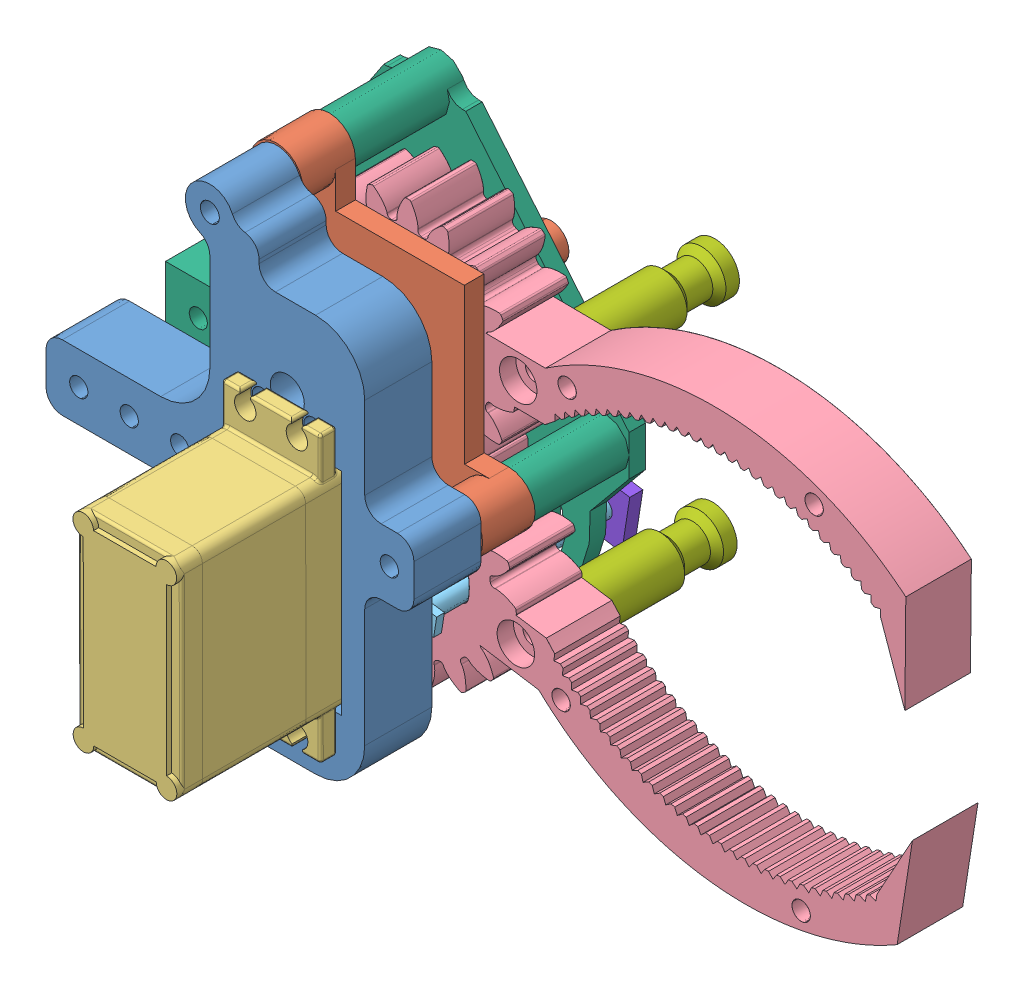
SolidWorks assembly GripperSlotAssemblyNoTop, configuration Default. Lengths in mm.
Overall size (145.62 102 92.76).
10 component instances, 8 part files, 25 mates.
Components (placement in the parent):
- ServoHolderBracketNew-1: ServoHolderBracketNew [Default] at (6.3729 56.0848 81.9147) size (71.28 93.53 13)
- MiddlePlate-1: MiddlePlate [Default] at (38.1308 58.971 75.5647) x (-0.001548 0.999999 0) z (-0.999999 -0.001548 0) size (94.08 38.1 44.92)
- Servo 20kg elbow and gripper2-1: Servo 20kg elbow and gripper2 [Default] at (53.154 53.241 126.4147) x (0.001242 -0.999999 0) z (0.999999 0.001242 0) size (55.1 45.65 20.12)
- NewFingerSlot-1: NewFingerSlot [Default] at (53.0922 81.5431 59.0547) x (0.009287 0.999957 0) z (0 0 1) size (42.33 117.57 12.7)
- NewFingerSlot-2: NewFingerSlot [Default] at (53.1512 43.4431 71.7547) x (-0.154386 -0.988011 0) z (0 0 -1) size (42.33 117.57 12.7)
- ServoHornWithSlotAttachment-1: ServoHornWithSlotAttachment [Default] at (53.1512 43.4431 79.6147) x (-0.988011 0.154386 0) z (0 0 1) size (23.98 21 43)
- GripperTopBracketNew-1: GripperTopBracketNew [Default] at (77.7117 20.5271 50.0377) x (-0.001548 0.999999 0) z (0 0 1) size (93.53 71.27 21.72)
- RubberBandStandOff-1: RubberBandStandOff [Default] at (74.6962 82.9427 46.3547) x (0.53743 -0.843308 0) z (0.843308 0.53743 0) size (9.53 25.4 9.53)
- RubberBandStandOff-2: RubberBandStandOff [Default] at (74.2353 38.5289 46.3547) x (0.873096 -0.487548 0) z (0.487548 0.873096 0) size (9.53 25.4 9.53)
- Connector Bracket-1: Connector Bracket [Default] at (58.9546 47.6779 43.8147) x (0.988011 -0.154386 0) z (0.154386 0.988011 0) size (19.05 2.54 10.16)
Mates (geometry in assembly coordinates):
- Concentric1: concentric aligned: circle of ServoHolderBracketNew-1; circle of MiddlePlate-1
- Coincident3: coincident anti-aligned: plane of ServoHolderBracketNew-1 through (6.3729 56.0848 81.9147) normal (0 0 -1); plane of MiddlePlate-1 through (38.0603 104.4687 81.9147) normal (0 0 1)
- Lock1: lock: unknown of ServoHolderBracketNew-1; unknown of MiddlePlate-1
- Concentric7: concentric aligned: circle of ServoHolderBracketNew-1; circle of Servo 20kg elbow and gripper2-1
- Coincident7: coincident anti-aligned: plane of ServoHolderBracketNew-1 through (6.3729 56.0848 94.9147) normal (0 0 1); plane of Servo 20kg elbow and gripper2-1 through (58.1851 28.1972 94.9147) normal (0 0 -1)
- Lock2: lock: unknown of ServoHolderBracketNew-1; unknown of Servo 20kg elbow and gripper2-1
- Concentric10: concentric anti-aligned: circle of MiddlePlate-1; circle of NewFingerSlot-1
- Coincident9: coincident anti-aligned: plane of MiddlePlate-1 through (38.1308 58.971 71.7547) normal (0 0 -1); plane of NewFingerSlot-1 through (53.0922 81.5431 71.7547) normal (0 0 1)
- Concentric11: concentric aligned: circle of MiddlePlate-1; circle of NewFingerSlot-2
- Coincident10: coincident anti-aligned: plane of MiddlePlate-1 through (38.1308 58.971 71.7547) normal (0 0 -1); plane of NewFingerSlot-2 through (53.1512 43.4431 71.7547) normal (0 0 1)
- GearMate4: gear = 7.112 : 7.112 mm: circle of NewFingerSlot-2; circle of NewFingerSlot-1
- Concentric13: concentric anti-aligned: circle of ServoHornWithSlotAttachment-1; circle of MiddlePlate-1
- Coincident11: coincident anti-aligned: plane of ServoHolderBracketNew-1 through (6.3729 56.0848 81.9147) normal (0 0 -1); plane of ServoHornWithSlotAttachment-1 through (53.1512 43.4431 81.9147) normal (0 0 1)
- Slot1: slot anti-aligned: cylinder of ServoHornWithSlotAttachment-1 through (63.1894 41.8745 42.1147) axis (0 0 1) radius 1.778; cylinder of NewFingerSlot-2 through (53.1512 43.4431 71.7547) axis (0 0 -1) radius 12.065; cylinder of NewFingerSlot-2 through (43.113 45.0117 71.7547) axis (0 0 -1) radius 1.905
- Concentric14: concentric aligned: circle of MiddlePlate-1; circle of GripperTopBracketNew-1
- Concentric15: concentric aligned: circle of MiddlePlate-1; circle of GripperTopBracketNew-1
- Coincident14: coincident anti-aligned: plane of MiddlePlate-1 through (38.1308 58.971 71.7547) normal (0 0 -1); plane of GripperTopBracketNew-1 through (38.0567 104.4738 71.7547) normal (0 0 1)
- Slot2: slot anti-aligned: cylinder of ServoHornWithSlotAttachment-1 through (63.1894 41.8745 42.1147) axis (0 0 1) radius 1.778; cylinder of GripperTopBracketNew-1 through (53.1512 43.4431 53.2127) axis (0 0 -1) radius 12.065; cylinder of GripperTopBracketNew-1 through (43.0814 42.0924 55.1177) axis (0 0 -1) radius 1.905
- Concentric17: concentric anti-aligned: circle of NewFingerSlot-1; circle of RubberBandStandOff-1
- Coincident17: coincident anti-aligned: plane of NewFingerSlot-1 through (53.0922 81.5431 59.0547) normal (0 0 -1); plane of RubberBandStandOff-1 through (77.2557 78.9264 59.0547) normal (0 0 1)
- Concentric18: concentric anti-aligned: circle of NewFingerSlot-2; circle of RubberBandStandOff-2
- Coincident19: coincident anti-aligned: plane of NewFingerSlot-2 through (53.1512 43.4431 59.0547) normal (0 0 -1); plane of RubberBandStandOff-2 through (78.3935 36.207 59.0547) normal (0 0 1)
- Concentric19: concentric aligned: circle of MiddlePlate-1; circle of Connector Bracket-1
- Concentric20: concentric aligned: circle of ServoHornWithSlotAttachment-1; circle of Connector Bracket-1
- Coincident22: coincident anti-aligned: plane of MiddlePlate-1 through (38.1308 58.971 43.8147) normal (0 0 -1); plane of Connector Bracket-1 through (58.9546 47.6779 43.8147) normal (0 0 1)
